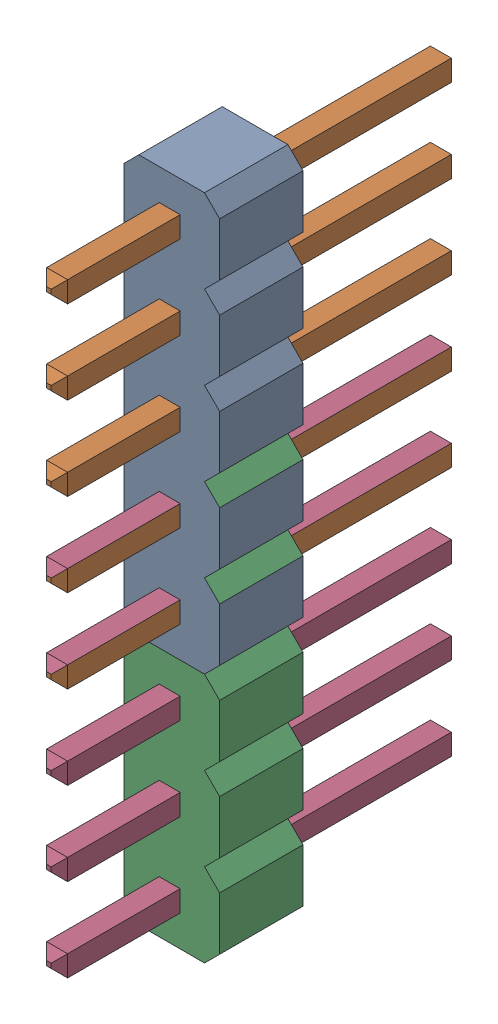
SolidWorks assembly Free-Models.step, configuration Default. Lengths in mm.
Overall size (2.92 20.32 12.19).
6 component instances, 2 part files, 0 mates.
Components (placement in the parent):
- 1240637040.step-1: 1240637040.step [Default] at (97.7778 84.836 -1.6002) x (0 -1 0) z (1 0 0) size (12.7 12.19 2.92)
  - User_Library-PinHeaderX5-1_PinHeaderX5_Body_1.step-1: User_Library-PinHeaderX5-1_PinHeaderX5_Body_1.step [Default] at origin size (12.7 2.54 2.92)
  - User_Library-PinHeaderX5-1_PinHeaderX5_Pins_1.step-1: User_Library-PinHeaderX5-1_PinHeaderX5_Pins_1.step [Default] at origin size (10.8 12.19 0.64)
- 1240637040.step-2: 1240637040.step [Default] at (97.7778 77.216 -1.6002) x (0 -1 0) z (1 0 0) size (12.7 12.19 2.92)
  - User_Library-PinHeaderX5-1_PinHeaderX5_Body_1.step-1: User_Library-PinHeaderX5-1_PinHeaderX5_Body_1.step [Default] at origin size (12.7 2.54 2.92)
  - User_Library-PinHeaderX5-1_PinHeaderX5_Pins_1.step-1: User_Library-PinHeaderX5-1_PinHeaderX5_Pins_1.step [Default] at origin size (10.8 12.19 0.64)
